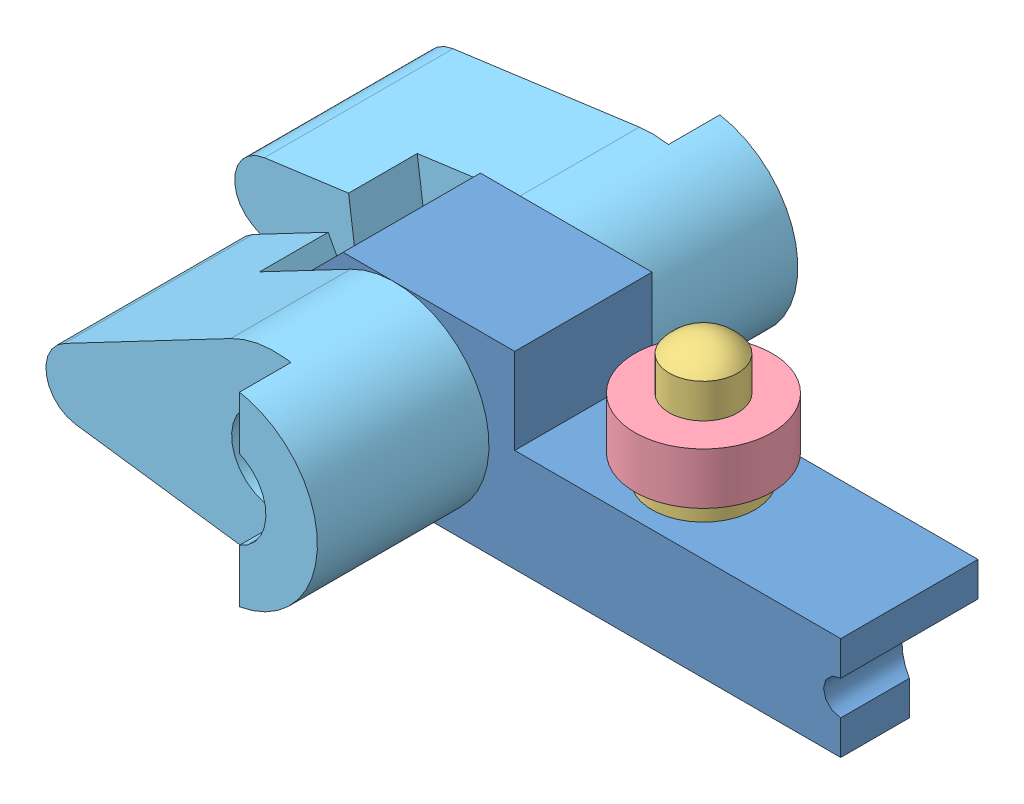
SolidWorks assembly pene lançant, configuration Défaut. Lengths in mm.
Overall size (40.25 15.66 28).
6 component instances, 5 part files, 14 mates.
Components (placement in the parent):
- Pièce5-1: Pièce5 [Défaut] at (-12.8916 -3.2369 -4) size (32 11 8)
- Pièce4-1: Pièce4 [Défaut] at (-6.8916 2.2631 10.5) x (0 0 -1) z (1 0 0) size (21 6 6)
- axe de noix-1: axe de noix [Défaut] at (7.1084 -5.2369 0) x (0 1 0) z (0 0 1) size (15.4 6 6)
- Pièce6-1: Pièce6 [Défaut] at (7.1084 4.1631 0) x (0.982348 0 0.187064) z (0 1 0) size (8 8 3)
- Pièce3-3: Pièce3 [Défaut] at (-6.8916 2.2631 -14) x (0.984808 -0.173648 0) z (0 0 1) size (19 11 14)
- Pièce3-4: Pièce3 [Défaut] at (-6.8916 2.2631 14) x (0.984808 0.173648 0) z (0 0 -1) size (19 11 14)
Mates (geometry in assembly coordinates):
- Coaxiale1: concentric anti-aligned: cylinder of Pièce5-1 through (-6.8916 2.2631 4) axis (0 0 -1) radius 3; cylinder of Pièce4-1 through (-6.8916 2.2631 65.3246) axis (0 0 1) radius 3
- Coïncidente1: coincident aligned: plane of Pièce5-1 through (-12.8916 2.7631 4) normal (0 0 1); plane of Pièce4-1 through (-6.8916 4.7631 4) normal (0 0 1)
- Coaxiale5: concentric anti-aligned: cylinder of Pièce5-1 through (7.1084 7.7631 0) axis (0 -1 0) radius 2; cylinder of axe de noix-1 through (7.1084 9.1631 0) axis (0 1 0) radius 2
- Coïncidente4: coincident anti-aligned: plane of Pièce5-1 through (19.1084 2.7631 4) normal (0 1 0); plane of axe de noix-1 through (5.1084 2.7631 0) normal (0 -1 0)
- Coaxiale6: concentric anti-aligned: cylinder of axe de noix-1 through (7.1084 9.1631 0) axis (0 1 0) radius 2; cylinder of Pièce6-1 through (7.1084 7.1631 0) axis (0 -1 0) radius 2
- Coïncidente5: coincident anti-aligned: plane of axe de noix-1 through (4.1084 4.1631 0) normal (0 1 0); plane of Pièce6-1 through (7.1084 4.1631 0) normal (0 -1 0)
- Coaxiale2: concentric anti-aligned: cylinder of Pièce4-1 through (-6.8916 2.2631 65.3246) axis (0 0 1) radius 2.5; cylinder of Pièce3-3 through (-6.8916 2.2631 0) axis (0 0 -1) radius 2.5
- Coïncidente2: coincident anti-aligned: plane of Pièce5-1 through (-12.8916 2.7631 -4) normal (0 0 -1); plane of Pièce3-3 through (-6.8916 2.2631 -4) normal (0 0 1)
- Parallèle1: parallel aligned: plane of Pièce5-1 through (-12.8916 -3.2369 4) normal (-1 0 0); plane of Pièce3-3 through (-5.9366 5.9476 -11) normal (-1 0 0)
- Coaxiale4: concentric aligned: cylinder of Pièce4-1 through (-6.8916 2.2631 65.3246) axis (0 0 1) radius 2.5; cylinder of Pièce3-4 through (-6.8916 2.2631 0) axis (0 0 1) radius 2.5
- Coïncidente3: coincident anti-aligned: plane of Pièce5-1 through (-12.8916 2.7631 4) normal (0 0 1); plane of Pièce3-4 through (-6.8916 2.2631 4) normal (0 0 -1)
- Coïncidente6: coincident aligned: plane of Pièce3-3 through (-5.9366 5.9476 -11) normal (-1 0 0); plane of Pièce3-4 through (-5.9366 -1.4213 11) normal (-1 0 0)
- Coïncidente9: coincident aligned: plane of Pièce3-3 through (-7.6303 7.7133 0) normal (-0.134314 0.990939 0); plane of Pièce3-4
- Parallèle2: parallel aligned: plane of Pièce5-1 through (-12.8916 -3.2369 4) normal (-1 0 0); plane of Pièce3-4
